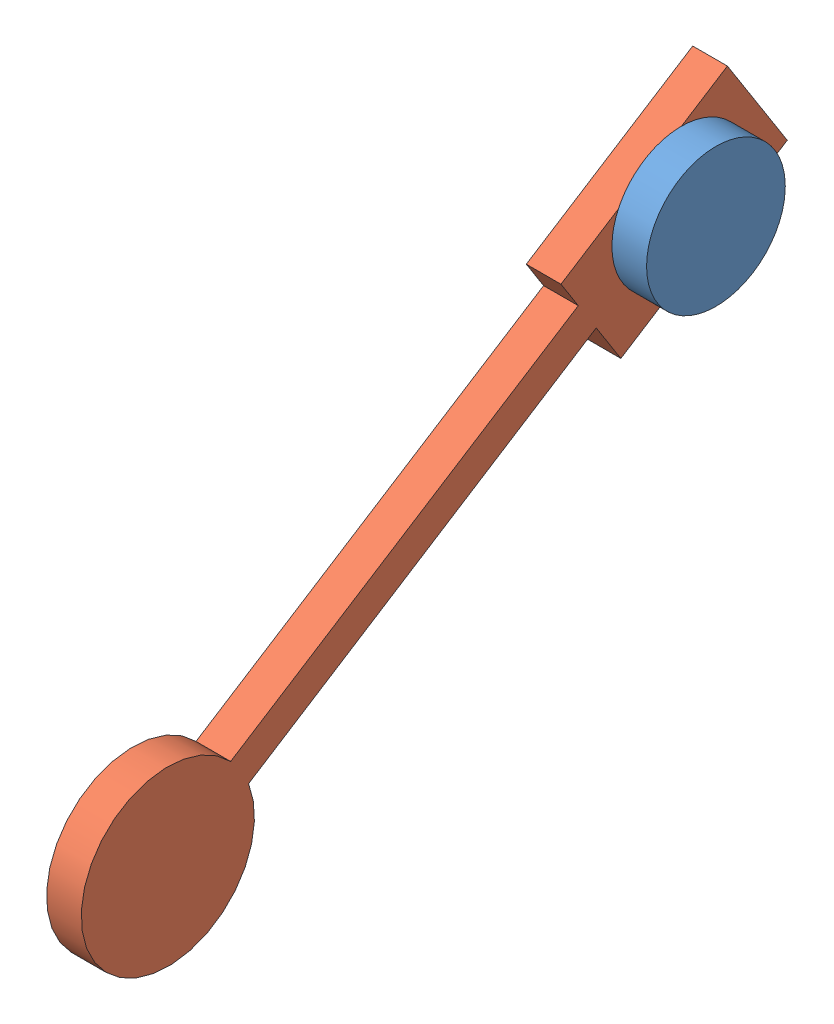
SolidWorks assembly Assem2, configuration Default. Lengths in mm.
Overall size (20 162.95 216.86).
2 component instances, 2 part files, 2 mates.
Components (placement in the parent):
- support-1: support [Default] at (-2.0905 20.1907 40.1498) size (10 40 40)
- pendulum-1: pendulum [Default] at (-2.0905 20.1907 40.1498) x (0 -0.536318 0.844016) z (-1 0 0) size (225.18 49.98 10)
Mates (geometry in assembly coordinates):
- Concentric1: concentric anti-aligned: cylinder of support-1 through (7.9095 20.1907 40.1498) axis (-1 0 0) radius 20; cylinder of pendulum-1 through (-12.0905 20.1907 40.1498) axis (1 0 0) radius 10
- Coincident2: coincident anti-aligned: plane of support-1 through (-2.0905 20.1907 40.1498) normal (-1 0 0); plane of pendulum-1 through (-2.0905 -70.6955 188.2346) normal (1 0 0)
